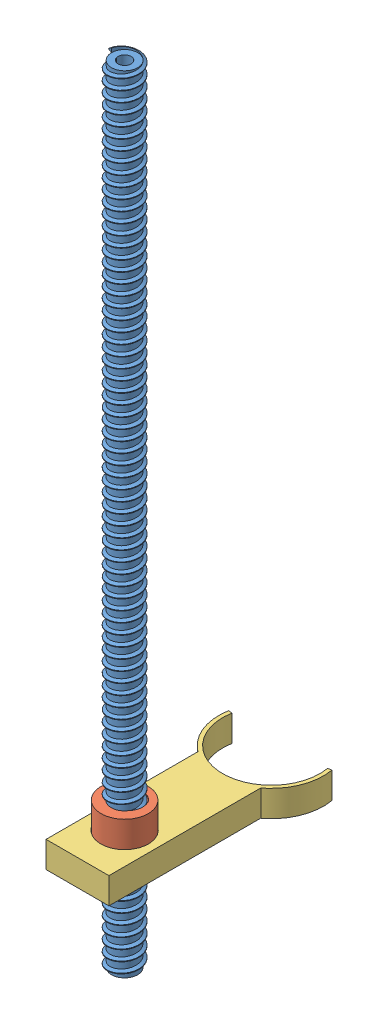
SolidWorks assembly guide_rail assembly, configuration Default. Lengths in mm.
Overall size (20 150.75 38.74).
3 component instances, 3 part files, 3 mates.
Components (placement in the parent):
- Part1^guide_rail assembly-1: Part1^guide_rail assembly [Default] at (1.0857 150 9.4599) x (1 0 0) z (0 -1 0) size (6.08 7.02 150.75) (virtual)
- Part2^guide_rail assembly-1: Part2^guide_rail assembly [Default] at (1.0857 17.6602 9.4599) x (0.870887 0 0.491483) z (-0.491483 0 0.870887) size (9 10.91 9) (virtual)
- Part3^guide_rail assembly-1: Part3^guide_rail assembly [Default] at (1.0857 22.6602 9.4599) x (1 0 0) z (0 -1 0) size (20 38.74 28.35) (virtual)
Mates (geometry in assembly coordinates):
- Concentric1: concentric anti-aligned: cylinder of Part1^guide_rail assembly-1 through (1.0857 0 9.4599) axis (0 1 0) radius 2.5; cylinder of Part2^guide_rail assembly-1 through (1.0857 27.6602 9.4599) axis (0 -1 0) radius 4.5
- Concentric2: concentric anti-aligned: cylinder of Part2^guide_rail assembly-1 through (1.0857 27.6602 9.4599) axis (0 -1 0) radius 4.5; cylinder of Part3^guide_rail assembly-1 through (1.0857 17.6602 9.4599) axis (0 1 0) radius 4.55
- Coincident1: coincident aligned: plane of Part2^guide_rail assembly-1 through (1.0857 17.6602 9.4599) normal (0 -1 0); plane of Part3^guide_rail assembly-1 through (1.0857 17.6602 9.4599) normal (0 -1 0)
